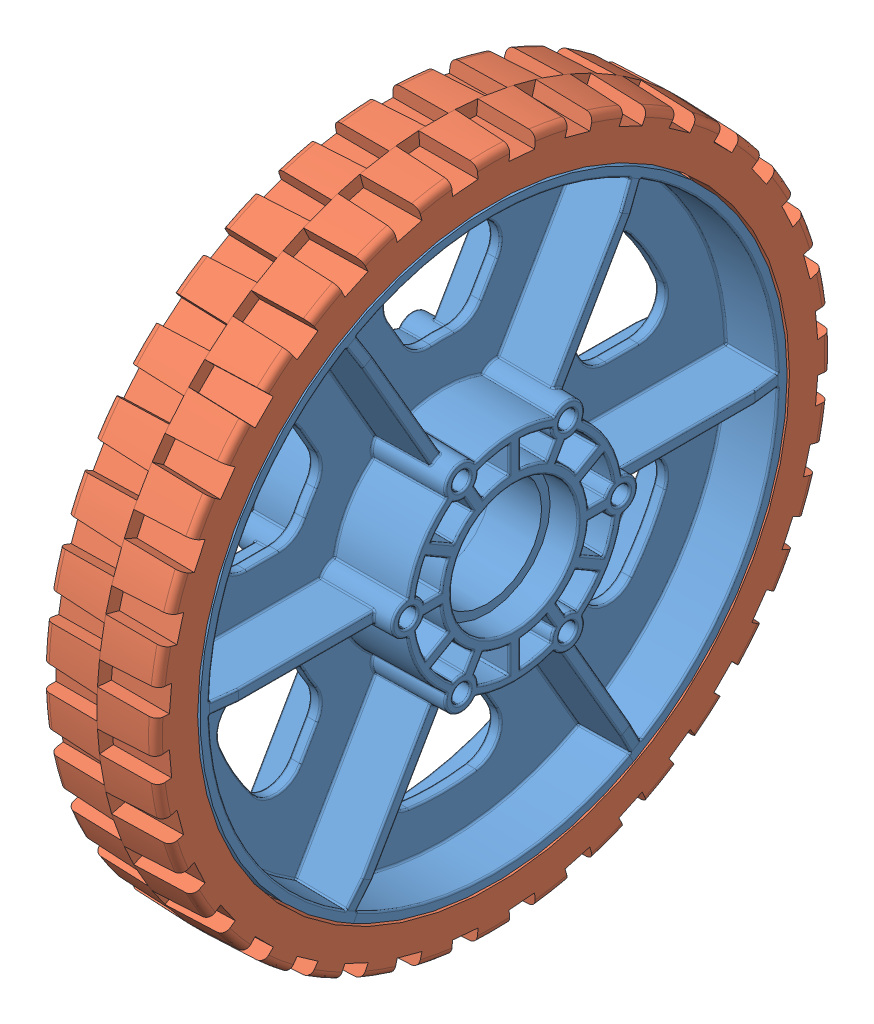
SolidWorks assembly am-0940b 6 in HiGrip Wheel, configuration Default. Lengths in mm.
Overall size (34.94 152.4 152.4).
2 component instances, 2 part files, 0 mates.
Components (placement in the parent):
- 6 wheel Rev 4-1: 6 wheel Rev 4 [Default] at (-52.6446 9.4231 21.378) size (34.94 132.08 132.08)
- 6 wheel tread II-1: 6 wheel tread II [Default] at (-65.3446 9.4231 21.378) x (0 0 -1) z (1 0 0) size (152.4 152.4 25.61)
